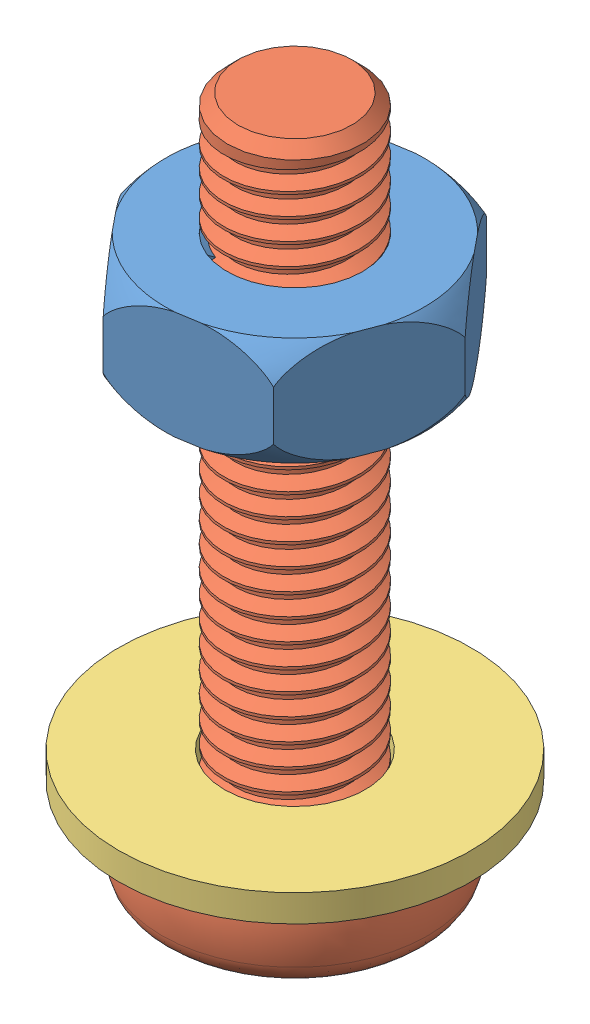
SolidWorks assembly Screw 3mm total Asm, configuration Default. Lengths in mm.
Overall size (8.57 15.29 8.76).
3 component instances, 3 part files, 3 mates.
Components (placement in the parent):
- Nut 3 mm-1: Nut 3 mm [Default] at (-6.9703 -2.6351 12.8014) x (0.355877 0 -0.934533) z (0.934533 0 0.355877) size (6.87 2.69 6.56)
- Screw 3mm-1: Screw 3mm [Default] at (-6.97 -14.6573 12.8027) x (0 0 -1) z (-1 0 0) size (6 15.29 6)
- Ross 3 mm-1: Ross 3 mm [Default] at (-6.9707 -11.1453 12.802) size (7.8 0.6 7.8)
Mates (geometry in assembly coordinates):
- Concentric1: concentric anti-aligned: circle of Nut 3 mm-1; cylinder of Screw 3mm-1 through (-6.9707 1.2547 12.802) axis (0 -1 0) radius 1.5
- Concentric2: concentric aligned: circle of Screw 3mm-1; circle of Ross 3 mm-1
- Coincident1: coincident anti-aligned: plane of Screw 3mm-1 through (-6.9707 -11.9453 9.9736) normal (0 1 0); plane of Ross 3 mm-1 through (-6.9707 -11.9453 12.802) normal (0 -1 0)
